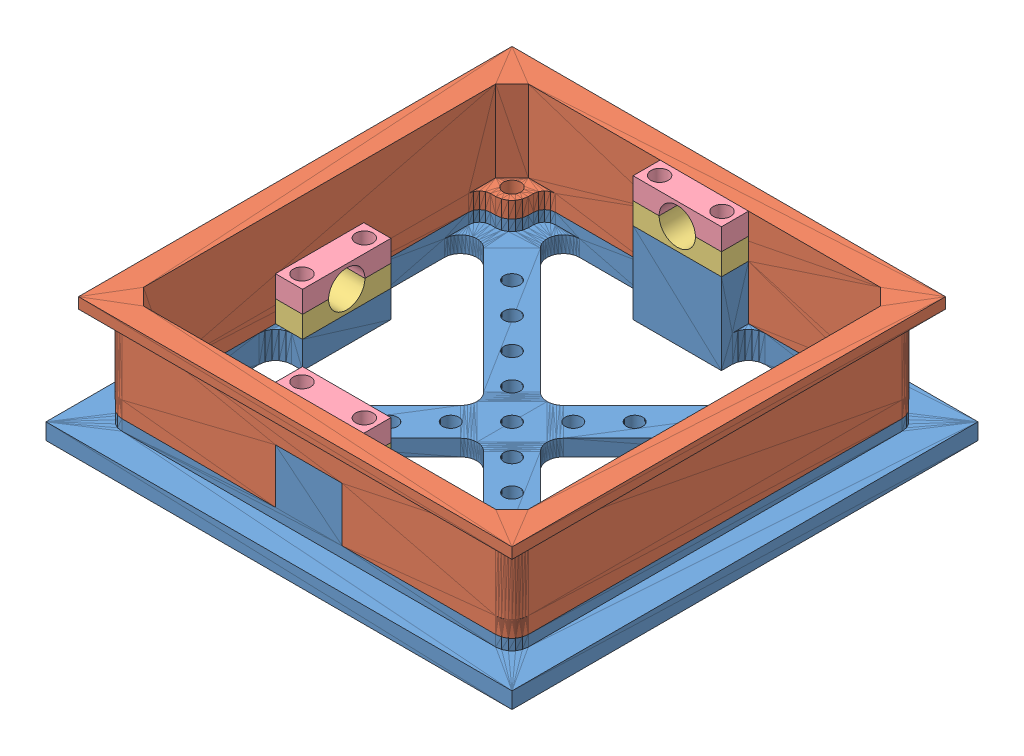
SolidWorks assembly AirCore11Assembly, configuration Default. Lengths in mm.
Overall size (86 23 86).
10 component instances, 4 part files, 26 mates.
Components (placement in the parent):
- Component1_v3-1: Component1_v3 [Default] at (11.6752 -56.6581 22.8365) x (-1 0 0) z (0 0 1) size (86 15.05 86)
- Component2_v3-1: Component2_v3 [Default] at (11.6752 -56.6581 22.8365) x (-1 0 0) z (0 0 1) size (80 18 80)
- RodHatBase-1: RodHatBase [Default] at (-31.3248 -33.6581 35.3365) x (-1 0 0) z (0 0 1) size (16.31 4 5)
- RodHatBase-2: RodHatBase [Default] at (-31.3248 -33.6581 101.3365) x (-1 0 0) z (0 0 1) size (16.31 4 5)
- RodHatBase-3: RodHatBase [Default] at (-61.8248 -43.6581 65.8365) x (0 0 1) z (1 0 0) size (16.31 4 5)
- RodHatBase-4: RodHatBase [Default] at (4.1752 -43.6581 65.8365) x (0 0 1) z (1 0 0) size (16.31 4 5)
- RodHatTop-1: RodHatTop [Default] at (-31.3248 -29.6581 35.3365) size (16.31 4 5)
- RodHatTop-2: RodHatTop [Default] at (-31.3248 -29.6581 101.3365) size (16.31 4 5)
- RodHatTop-3: RodHatTop [Default] at (-61.8248 -39.6581 65.8365) x (0 0 -1) z (1 0 0) size (16.31 4 5)
- RodHatTop-4: RodHatTop [Default] at (4.1752 -39.6581 65.8365) x (0 0 -1) z (1 0 0) size (16.31 4 5)
Mates (geometry in assembly coordinates):
- Coincident1: coincident aligned: line of Component1_v3-1 through (-37.4798 -45.6581 103.3365) axis (-1 0 0); line of Component2_v3-1 through (-37.4798 -45.6581 103.3365) axis (-1 0 0)
- Coincident2: coincident: point of Component1_v3-1; point of Component2_v3-1
- Coincident3: coincident aligned: line of Component1_v3-1 through (-25.1698 -35.6581 103.3365) axis (-1 0 0); line of Component2_v3-1 through (-25.1698 -35.6581 103.3365) axis (-1 0 0)
- Coincident4: coincident anti-aligned: line of Component1_v3-1 through (-39.4798 -35.6581 35.3365) axis (1 0 0); line of RodHatBase-1 through (-23.1698 -35.6581 35.3365) axis (-1 0 0)
- Coincident5: coincident: point of Component1_v3-1; point of RodHatBase-1
- Coincident6: coincident anti-aligned: line of Component1_v3-1 through (-23.1698 -35.6581 35.3365) axis (0 0 -1); line of RodHatBase-1 through (-23.1698 -35.6581 30.3365) axis (0 0 1)
- Coincident7: coincident anti-aligned: line of Component1_v3-1 through (-23.1698 -35.6581 101.3365) axis (0 0 -1); line of RodHatBase-2 through (-23.1698 -35.6581 96.3365) axis (0 0 1)
- Coincident8: coincident aligned: line of Component1_v3-1 through (-23.1698 -35.6581 96.3365) axis (-1 0 0); line of RodHatBase-2 through (-23.1698 -35.6581 96.3365) axis (-1 0 0)
- Coincident9: coincident anti-aligned: line of Component1_v3-1 through (-61.8248 -45.6581 73.9915) axis (0 0 -1); line of RodHatBase-3 through (-61.8248 -45.6581 57.6815) axis (0 0 1)
- Coincident10: coincident: point of Component1_v3-1; point of RodHatBase-3
- Coincident11: coincident aligned: line of Component1_v3-1 through (-0.8248 -45.6581 57.6815) axis (0 0 1); line of RodHatBase-4 through (-0.8248 -45.6581 57.6815) axis (0 0 1)
- Coincident12: coincident: point of Component1_v3-1; point of RodHatBase-4
- Concentric1: concentric aligned: circle of RodHatBase-1; circle of RodHatTop-1
- Coincident14: coincident aligned: line of RodHatBase-1 through (-39.4798 -31.6581 30.3365) axis (0 0 1); line of RodHatTop-1 through (-39.4798 -31.6581 30.3365) axis (0 0 1)
- Coincident15: coincident anti-aligned: line of RodHatBase-1 through (-34.6798 -31.6581 35.3365) axis (-1 0 0); line of RodHatTop-1 through (-39.4798 -31.6581 35.3365) axis (1 0 0)
- Parallel1: parallel anti-aligned: line of Component2_v3-1 through (1.1752 -27.6581 101.3365) axis (-1 0 0); line of RodHatTop-2 through (-39.4798 -27.6581 101.3365) axis (1 0 0)
- Concentric2: concentric aligned: circle of RodHatBase-2; circle of RodHatTop-2
- Coincident18: coincident anti-aligned: line of RodHatBase-2 through (-23.1698 -31.6581 96.3365) axis (-1 0 0); line of RodHatTop-2 through (-27.9698 -31.6581 96.3365) axis (1 0 0)
- Coincident23: coincident: point of RodHatBase-2; point of RodHatTop-2
- Coincident24: coincident: point of RodHatBase-2; point of RodHatTop-2
- Coincident25: coincident aligned: line of RodHatBase-3 through (-66.8248 -41.6581 73.9915) axis (1 0 0); line of RodHatTop-3 through (-66.8248 -41.6581 73.9915) axis (1 0 0)
- Concentric3: concentric aligned: circle of RodHatBase-3; circle of RodHatTop-3
- Coincident27: coincident: point of RodHatBase-3; point of RodHatTop-3
- Coincident28: coincident aligned: line of RodHatBase-4 through (-0.8248 -41.6581 73.9915) axis (1 0 0); line of RodHatTop-4 through (-0.8248 -41.6581 73.9915) axis (1 0 0)
- Concentric4: concentric aligned: circle of RodHatBase-4; circle of RodHatTop-4
- Coincident30: coincident: point of RodHatBase-4; point of RodHatTop-4
